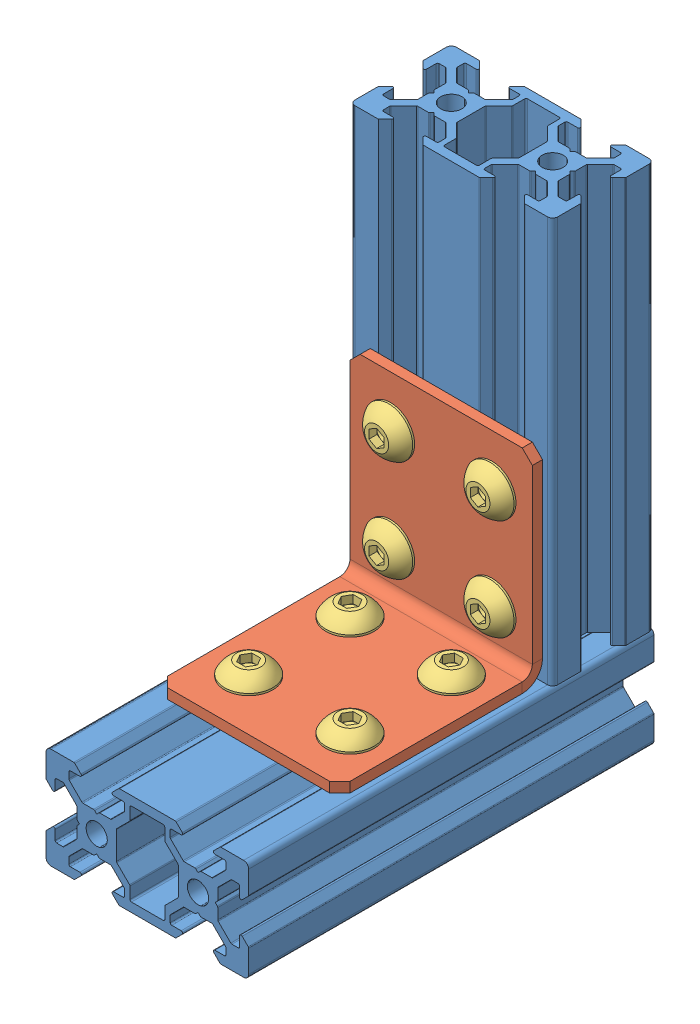
SolidWorks assembly Уголок 20 серия 2х4 40х40х36х2 СБ, configuration По умолчанию. Lengths in mm.
Overall size (40 100 80).
11 component instances, 3 part files, 22 mates.
Components (placement in the parent):
- 204090-1: 204090 [По умолчанию] at origin size (40 20 80)
- 204090-2: 204090 [По умолчанию] at (0 10 10) x (1 0 0) z (0 1 0) size (40 20 80)
- Уголок 20 серия 2х4 40х40х36х2-1: Уголок 20 серия 2х4 40х40х36х2 [По умолчанию] at (10 10 20) size (36 40 40)
- socket button head screw_iso-1: socket button head screw_iso [ISO 7380 - M5 x 10 - 10N] at (0 14.75 30) x (0 -1 0) z (0 0 1) size (12.75 9.5 9.5)
- socket button head screw_iso-2: socket button head screw_iso [ISO 7380 - M5 x 10 - 10N] at (0 14.75 50) x (0 -1 0) z (0 0 1) size (12.75 9.5 9.5)
- socket button head screw_iso-3: socket button head screw_iso [ISO 7380 - M5 x 10 - 10N] at (20 14.75 50) x (0 -1 0) z (0 0 1) size (12.75 9.5 9.5)
- socket button head screw_iso-4: socket button head screw_iso [ISO 7380 - M5 x 10 - 10N] at (20 14.75 30) x (0 -1 0) z (0 0 1) size (12.75 9.5 9.5)
- socket button head screw_iso-5: socket button head screw_iso [ISO 7380 - M5 x 10 - 10N] at (0 20 24.75) x (0 0 -1) z (1 0 0) size (12.75 9.5 9.5)
- socket button head screw_iso-6: socket button head screw_iso [ISO 7380 - M5 x 10 - 10N] at (0 40 24.75) x (0 0 -1) z (1 0 0) size (12.75 9.5 9.5)
- socket button head screw_iso-7: socket button head screw_iso [ISO 7380 - M5 x 10 - 10N] at (20 40 24.75) x (0 0 -1) z (1 0 0) size (12.75 9.5 9.5)
- socket button head screw_iso-8: socket button head screw_iso [ISO 7380 - M5 x 10 - 10N] at (20 20 24.75) x (0 0 -1) z (1 0 0) size (12.75 9.5 9.5)
Mates (geometry in assembly coordinates):
- Совпадение1: coincident aligned: plane of 204090-1 through (30 10 80) normal (1 0 0); plane of 204090-2 through (30 90 20) normal (1 0 0)
- Совпадение2: coincident anti-aligned: plane of 204090-1 through (30 10 80) normal (0 1 0); plane of 204090-2 through (0 10 10) normal (0 -1 0)
- Совпадение5: coincident aligned: plane of 204090-1 through (0 0 0) normal (0 0 -1); plane of 204090-2 through (30 90 0) normal (0 0 -1)
- Совпадение6: coincident anti-aligned: plane of 204090-1 through (15.6 10 80) normal (0 1 0); plane of Уголок 20 серия 2х2 20х20х36х2-1 through (10 10 20) normal (0 -1 0)
- Совпадение7: coincident anti-aligned: plane of 204090-2 through (15.6 90 20) normal (0 0 1); plane of Уголок 20 серия 2х2 20х20х36х2-1 through (10 10 20) normal (0 0 -1)
- Расстояние1: distance = 2 mm aligned: plane of Уголок 20 серия 2х2 20х20х36х2-1 through (28 10 60) normal (1 0 0); plane of 204090-1 through (30 10 80) normal (1 0 0)
- Концентричный1: concentric aligned: cylinder of Уголок 20 серия 2х4 40х40х36х2-1 through (0 12 30) axis (0 1 0) radius 2.75; cylinder of socket button head screw_iso-1 through (0 14.75 30) axis (0 1 0) radius 4.75
- Совпадение8: coincident anti-aligned: plane of Уголок 20 серия 2х4 40х40х36х2-1 through (10 12 20) normal (0 1 0); plane of socket button head screw_iso-1 through (2.5 12 30) normal (0 -1 0)
- Концентричный2: concentric aligned: cylinder of Уголок 20 серия 2х4 40х40х36х2-1 through (0 12 50) axis (0 1 0) radius 2.75; cylinder of socket button head screw_iso-2 through (0 14.75 50) axis (0 1 0) radius 4.75
- Совпадение9: coincident anti-aligned: plane of Уголок 20 серия 2х4 40х40х36х2-1 through (10 12 20) normal (0 1 0); plane of socket button head screw_iso-2 through (2.5 12 50) normal (0 -1 0)
- Концентричный3: concentric aligned: cylinder of Уголок 20 серия 2х4 40х40х36х2-1 through (20 12 50) axis (0 1 0) radius 2.75; cylinder of socket button head screw_iso-3 through (20 14.75 50) axis (0 1 0) radius 4.75
- Совпадение10: coincident anti-aligned: plane of Уголок 20 серия 2х4 40х40х36х2-1 through (10 12 20) normal (0 1 0); plane of socket button head screw_iso-3 through (22.5 12 50) normal (0 -1 0)
- Концентричный4: concentric aligned: cylinder of Уголок 20 серия 2х4 40х40х36х2-1 through (20 12 30) axis (0 1 0) radius 2.75; cylinder of socket button head screw_iso-4 through (20 14.75 30) axis (0 1 0) radius 4.75
- Совпадение11: coincident anti-aligned: plane of Уголок 20 серия 2х4 40х40х36х2-1 through (10 12 20) normal (0 1 0); plane of socket button head screw_iso-4 through (22.5 12 30) normal (0 -1 0)
- Концентричный5: concentric aligned: cylinder of Уголок 20 серия 2х4 40х40х36х2-1 through (0 20 22) axis (0 0 1) radius 2.75; cylinder of socket button head screw_iso-5 through (0 20 24.75) axis (0 0 1) radius 4.75
- Совпадение12: coincident anti-aligned: plane of Уголок 20 серия 2х4 40х40х36х2-1 through (10 10 22) normal (0 0 1); plane of socket button head screw_iso-5 through (0 22.5 22) normal (0 0 -1)
- Концентричный6: concentric aligned: cylinder of Уголок 20 серия 2х4 40х40х36х2-1 through (0 40 22) axis (0 0 1) radius 2.75; cylinder of socket button head screw_iso-6 through (0 40 24.75) axis (0 0 1) radius 4.75
- Совпадение13: coincident anti-aligned: plane of Уголок 20 серия 2х4 40х40х36х2-1 through (10 10 22) normal (0 0 1); plane of socket button head screw_iso-6 through (0 42.5 22) normal (0 0 -1)
- Концентричный7: concentric aligned: cylinder of Уголок 20 серия 2х4 40х40х36х2-1 through (20 40 22) axis (0 0 1) radius 2.75; cylinder of socket button head screw_iso-7 through (20 40 24.75) axis (0 0 1) radius 4.75
- Совпадение14: coincident anti-aligned: plane of Уголок 20 серия 2х4 40х40х36х2-1 through (10 10 22) normal (0 0 1); plane of socket button head screw_iso-7 through (20 42.5 22) normal (0 0 -1)
- Концентричный8: concentric aligned: cylinder of Уголок 20 серия 2х4 40х40х36х2-1 through (20 20 22) axis (0 0 1) radius 2.75; cylinder of socket button head screw_iso-8 through (20 20 24.75) axis (0 0 1) radius 4.75
- Совпадение15: coincident anti-aligned: plane of Уголок 20 серия 2х4 40х40х36х2-1 through (10 10 22) normal (0 0 1); plane of socket button head screw_iso-8 through (20 22.5 22) normal (0 0 -1)
